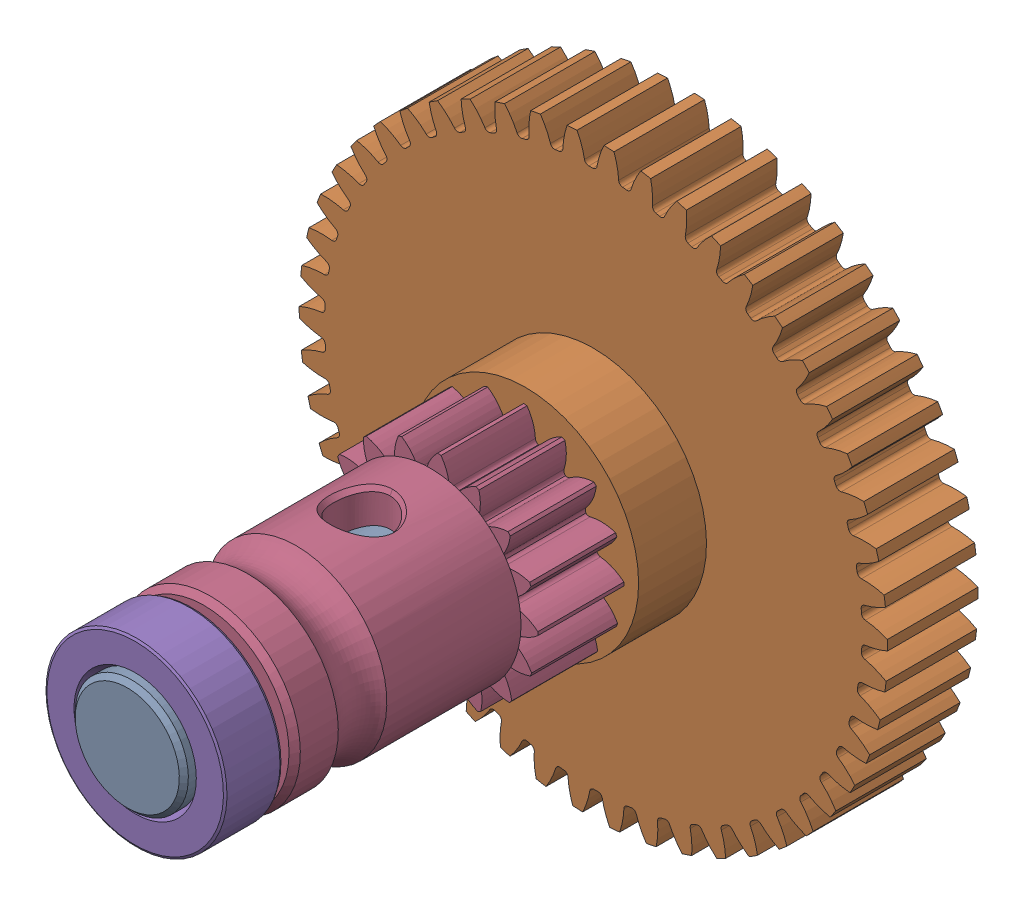
SolidWorks assembly BMG Drive Mechanism, configuration Default. Lengths in mm.
Overall size (30.26 30.24 28).
7 component instances, 4 part files, 0 mates.
Components (placement in the parent):
- Driveshaft Assembly-1: Driveshaft Assembly [Default] at (8.2341 -1.0595 -35) x (0.996195 0.087156 0) z (0 0 1) size (27.94 27.91 28)
  - Shaft-assembly-1: Shaft-assembly [Default] at (24.3081 94.4506 -53.9704) x (0 0 -1) z (0.077566 0.996987 0) size (28 26 25.97)
    - Shaft-assembly-1: Shaft-assembly [Default] at origin size (28 5 5)
    - Shaft-assembly_2-1: Shaft-assembly_2 [Default] at origin size (7.5 26 25.97)
  - MR825 Ballbearing 5x8x2-1: MR825 Ballbearing 5x8x2 [Default] at (20.7338 94.7286 -54.972) x (0.2227 -0.974887 0) z (0 0 1) size (8 8 2.5)
  - Direct_Drivegear-1: Direct_Drivegear [Default] at (20.7338 94.7286 -42.6707) x (-0.077566 -0.996987 0) z (0 0 1) size (9.47 9.43 13.8)
  - MR825 Ballbearing 5x8x2-2: MR825 Ballbearing 5x8x2 [Default] at (20.7338 94.7286 -29.8717) x (0.132022 -0.991247 0) z (0 0 1) size (8 8 2.5)
